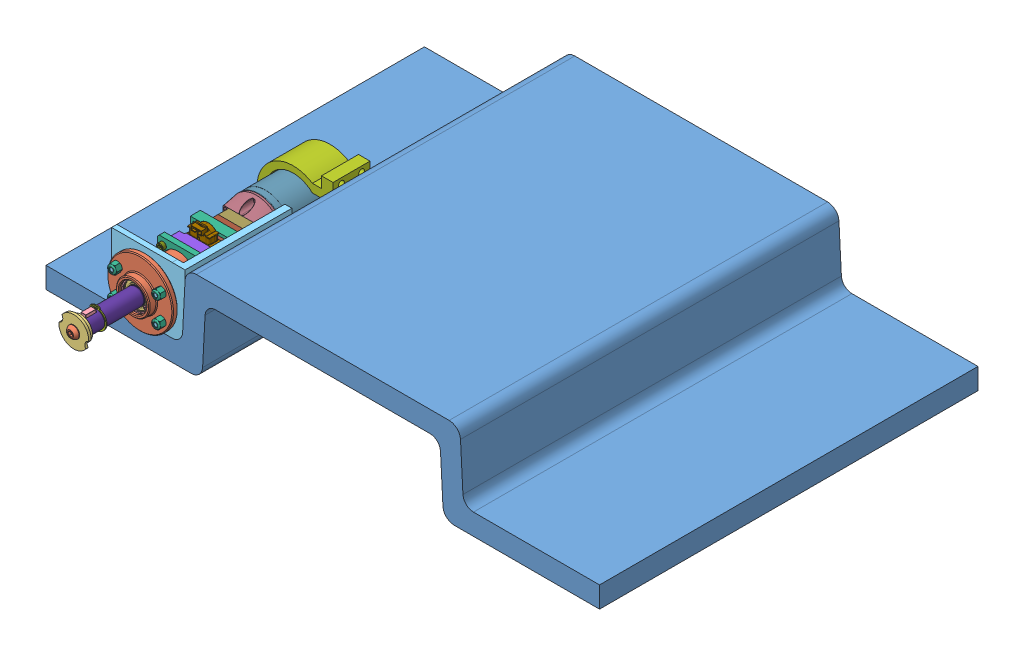
SolidWorks assembly assemblage final, configuration Default. Lengths in mm.
Overall size (658.2 105 569.67).
45 component instances, 25 part files, 3 mates.
Components (placement in the parent):
- Plancher simple-1: Plancher simple [Default] at (113.44 418.5296 542.7092) size (658.2 105 450)
- assemblage moteur et sol-2: assemblage moteur et sol [Default] at (-292.1256 -71.5682 -182.2443) size (163.91 93.83 344.65)
  - PB2023-M054 DRIVETRAIN ASSEMBLY-v1-1: PB2023-M054 DRIVETRAIN ASSEMBLY-v1 [Default] at (194.4247 468.0978 914.4535) x (0 1 0) z (0 0 1) size (93.83 163.91 344.65)
    - A12220103_FRONT_BRACKET_ASSEMBLY-1: A12220103_FRONT_BRACKET_ASSEMBLY [Default] at origin size (78 78 534.65)
      - A12220101_FRONT_CASE_ASSEMBLY-1: A12220101_FRONT_CASE_ASSEMBLY [Default] at origin size (78 78 141.2)
        - 12220103_FRONT_HOUSING-1: 12220103_FRONT_HOUSING [Default] at (-52 141.0744 -192.9876) x (0 0 -1) z (1 0 0) size (60 78 78)
        - BALL BEARING-1: BALL BEARING [6656K203] at origin size (32 32 10)
        - BALL BEARING-2: BALL BEARING [6656K203] at (0 0 41) size (32 32 10)
        - Internal Retaining Ring (98455A129)-1: Internal Retaining Ring (98455A129) [98455A129] at (0.0361 0.7992 46) x (0.998982 -0.045107 0) z (0 0 1) size (34.4 33.81 1.2)
      - M6 x 20mm Steel Hex Head Screw (91310A333)-2: M6 x 20mm Steel Hex Head Screw (91310A333) [91310A333] at (-15.125 -26.1973 37.15) x (0 0 1) z (-0.44141 0.897306 0) size (24.4 11.55 10)
      - M6 x 1mm Steel Hex LockNut (90592A016)-1: M6 x 1mm Steel Hex LockNut (90592A016) [97260A101] at (15.125 -26.1973 41.85) x (0.928554 -0.371196 0) z (-0.371196 -0.928554 0) size (10 8.38 11.55)
      - 20MM External Retaining Ring (98541A123)-4: 20MM External Retaining Ring (98541A123) [98541A123] at (0 0 92.94) x (0 0 1) z (-0.186581 0.98244 0) size (1.2 25.1 22.76)
      - A12220110_FRONT_SHAFT_ASSEMBLY-1: A12220110_FRONT_SHAFT_ASSEMBLY [Default] at (1.7896 0 -19.01) x (0 -1 0) z (0 0 1) size (64.01 67.32 307.03)
        - A12220105_MOTOR_BRACKET_ASSEMBLY-1: A12220105_MOTOR_BRACKET_ASSEMBLY [Default] at origin size (64.01 67.32 280.24) (flexible)
          - 12220106-051 MiniCIM Motor Assembly-1: 12220106-051 MiniCIM Motor Assembly [Default] at origin size (64.01 67.32 218.97)
            - Gearbox Assembly-1: Gearbox Assembly [Default] at (34.0244 -12.4567 -92.7758) x (0 0 1) z (-1 0 0) size (123.35 56.32 44.45)
              - Output Housing-2: Output Housing [Default] at (64.8023 -0.856 18.2213) x (1 0 0) z (0 -1 0) size (75.7 44.45 56.32)
                - Housing-1: Housing [Default] at (19.8785 -6.4219 -11.5232) size (18.13 44.45 42)
                - Encoder.step-1: Encoder.step [Default] at (12.6785 15.8031 -11.5232) x (0 0 1) z (-1 0 0) size (56.32 42 21.21)
                - Gearbox_output_shaft-1: Gearbox_output_shaft [Default] at origin size (63.51 17 17)
              - Ring Gears-1: Ring Gears [Default] at (71.9808 10.6671 11.7994) x (1 0 0) z (0 -1 0) size (32.2 42 42)
              - Ring Gear Stage 3-1: Ring Gear Stage 3 [Default] at (59.2808 10.6671 11.7994) x (1 0 0) z (0 -1 0) size (28.65 42 42)
            - CIM Adaptor.step-1: CIM Adaptor.step [Default] at (0 -1.7896 -68.72) x (0 -1 0) z (-1 0 0) size (64.01 21.63 64.01)
            - Mini CIM-1: Mini CIM [Default] at (0 -1.7896 -80.245) x (0 0 -1) z (1 0 0) size (101.22 64.01 64.01)
            - 8-32 X 3IN LG - Black-Oxide Alloy Steel Socket Head Screw (90044A516)-1: 8-32 X 3IN LG - Black-Oxide Alloy Steel Socket Head Screw (90044A516) [90044A516] at (17.5 15.7104 -75.245) x (-0.08536 0.99635 0) z (0 0 -1) size (6.86 6.86 81.33)
            - 8-32 X 3IN LG - Black-Oxide Alloy Steel Socket Head Screw (90044A516)-3: 8-32 X 3IN LG - Black-Oxide Alloy Steel Socket Head Screw (90044A516) [90044A516] at (-17.5 -19.2896 -75.245) x (-0.242255 0.970213 0) z (0 0 -1) size (6.86 6.86 81.33)
          - 10-32 X 0.875IN LG - Black-Oxide Alloy Steel Socket Head Screw (91251A346)-1: 10-32 X 0.875IN LG - Black-Oxide Alloy Steel Socket Head Screw (91251A346) [91251A346] at (-17.9605 16.1709 6.1805) x (0.130335 0.99147 0) z (0 0 1) size (7.94 7.94 27.67)
          - 10-32 X 0.875IN LG - Black-Oxide Alloy Steel Socket Head Screw (91251A346)-2: 10-32 X 0.875IN LG - Black-Oxide Alloy Steel Socket Head Screw (91251A346) [91251A346] at (17.9605 -19.7501 6.1805) x (0.872398 0.488796 0) z (0 0 1) size (7.94 7.94 27.67)
        - PB2023-M005 ROTARY SHAFT-1: PB2023-M005 ROTARY SHAFT [Default] at (0 -1.7896 136.57) x (0 0 -1) z (1 0 0) size (126.56 25 25)
        - 12220110_MOTOR_KEY-1: 12220110_MOTOR_KEY [Default] at (0 5.1764 16.3975) size (3.17 4.76 26.16)
      - M6 x 20mm Steel Hex Head Screw (91310A333)-7: M6 x 20mm Steel Hex Head Screw (91310A333) [91310A333] at (15.125 -26.1973 37.15) x (0 0 1) z (0.78025 0.625468 0) size (24.4 11.55 10)
      - M6 x 20mm Steel Hex Head Screw (91310A333)-9: M6 x 20mm Steel Hex Head Screw (91310A333) [91310A333] at (15.125 26.1973 37.15) x (0 0 1) z (0.877007 0.480477 0) size (24.4 11.55 10)
      - M6 x 20mm Steel Hex Head Screw (91310A333)-11: M6 x 20mm Steel Hex Head Screw (91310A333) [91310A333] at (-15.0958 26.1466 37.15) x (0 0 1) z (0.947118 0.320887 0) size (24.4 11.55 10)
      - M6 x 1mm Steel Hex LockNut (90592A016)-7: M6 x 1mm Steel Hex LockNut (90592A016) [97260A101] at (-15.125 -26.1973 41.85) x (0.975663 -0.219276 0) z (-0.219276 -0.975663 0) size (10 8.38 11.55)
      - M6 x 1mm Steel Hex LockNut (90592A016)-9: M6 x 1mm Steel Hex LockNut (90592A016) [97260A101] at (-15.125 26.1973 41.85) x (0.995642 -0.093258 0) z (-0.093258 -0.995642 0) size (10 8.38 11.55)
      - M6 x 1mm Steel Hex LockNut (90592A016)-11: M6 x 1mm Steel Hex LockNut (90592A016) [97260A101] at (15.2049 26.151 41.85) x (1 -0.000046 0) z (-0.000046 -1 0) size (10 8.38 11.55)
    - M6 x 25mm Steel Socket Head Screw (91290A330)-1: M6 x 25mm Steel Socket Head Screw (91290A330) [91290A330] at (-31.155 30 -64.48) x (0 -0.901175 -0.433456) z (1 0 0) size (10 10 31.46)
    - M6 x 1mm Steel Hex LockNut (90592A016)-1: M6 x 1mm Steel Hex LockNut (90592A016) [97260A101] at (-33 -30 -64.48) x (0 0.608626 0.793457) z (0 -0.793457 0.608626) size (10 8.38 11.55)
    - M6 x 1mm Steel Hex LockNut (90592A016)-2: M6 x 1mm Steel Hex LockNut (90592A016) [97260A101] at (-33 30 -64.48) x (0 -0.994883 0.101031) z (0 -0.101031 -0.994883) size (10 8.38 11.55)
    - M8 X 20MM - 18-8 Stainless Steel Button Head Hex Drive Screws (97763A444)-1: M8 X 20MM - 18-8 Stainless Steel Button Head Hex Drive Screws (97763A444) [97763A444] at (0 0 124.825) x (0.999813 0.019347 0) z (0 0 1) size (14 14 25.15)
    - PB2023-M006 WHEEL END CAP CUSTOM WASHER-1: PB2023-M006 WHEEL END CAP CUSTOM WASHER [Default] at (0 0 117.56) x (0 0 -1) z (-0.345262 -0.938506 0) size (8.5 35.5 34.05)
    - 98870A743_Machine Key-1: 98870A743_Machine Key [98870A743] at (10 0 103.06) size (6 6 12)
    - braquette bleu-1: braquette bleu [Default] at (-33 40 35.5) x (0 0 -1) z (0 -1 0) size (205.75 78 138.28)
    - braquette gearbox-3: braquette gearbox [Default] at (-21.66 25 -4.13) x (0 0 -1) z (-1 0 0) size (72.34 80.66 66.5)
    - braquette moteur- v2-1: braquette moteur- v2 [Default] at (0 -0.0033 -184.471) x (0 1 0) z (0 0 -1) size (123.62 80 44)
Mates (geometry in assembly coordinates):
- Coincident1: coincident anti-aligned: plane of Plancher simple-1 through (-215.66 363.5296 317.7092) normal (0 1 0); plane of assemblage moteur et sol-2/PB2023-M054 DRIVETRAIN ASSEMBLY-v1-1/braquette bleu-1 through (-57.7009 363.5296 767.7092) normal (0 -1 0)
- Coincident2: coincident aligned: plane of Plancher simple-1 through (-65.7009 376.0296 767.7092) normal (0 0 1); plane of assemblage moteur et sol-2/PB2023-M054 DRIVETRAIN ASSEMBLY-v1-1/braquette bleu-1 through (-57.7009 363.5296 767.7092) normal (0 0 1)
- Coincident3: coincident anti-aligned: plane of Plancher simple-1 through (-53.218 375.3754 317.7092) normal (-0.99863 0.052336 0); plane of assemblage moteur et sol-2/PB2023-M054 DRIVETRAIN ASSEMBLY-v1-1/braquette bleu-1 through (-50.3167 430.7362 681.8566) normal (0.99863 -0.052336 0)
